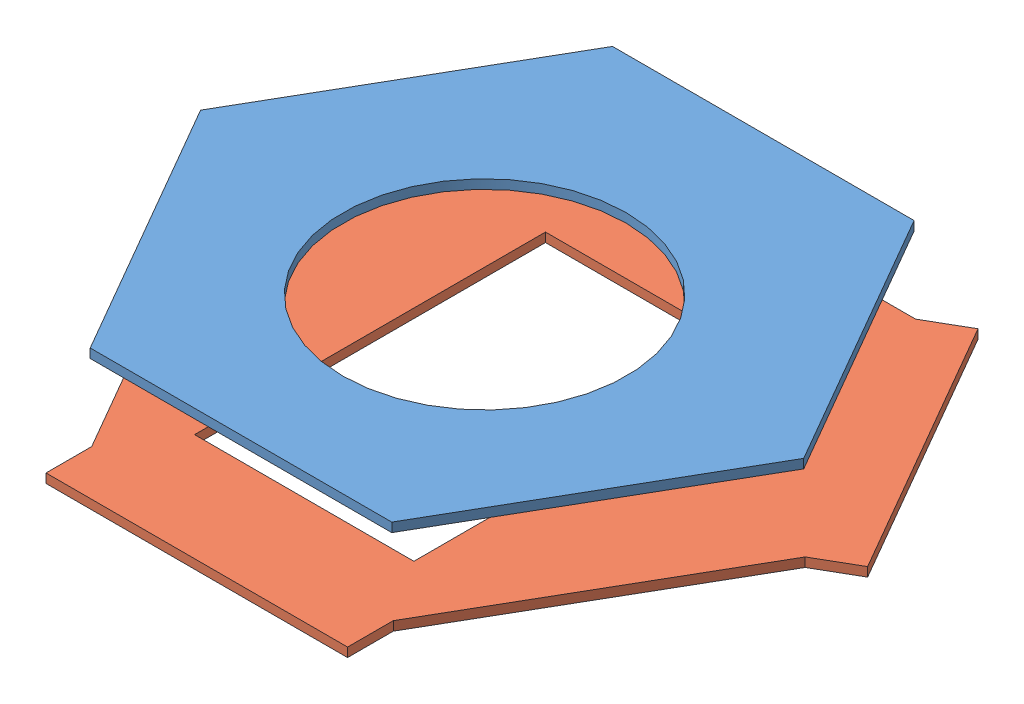
SolidWorks assembly Assem3, configuration Default. Lengths in mm.
Overall size (376.65 51.34 325.22).
2 component instances, 2 part files, 1 mates.
Components (placement in the parent):
- Mechanism Aperture-1: Mechanism Aperture [Default] at origin size (330 5 285.79)
- Mechanism Lock&Lock-1: Mechanism Lock&Lock [Default] at (0.7741 -46.3427 -0.04) size (376.65 5 325.22)
Mates (geometry in assembly coordinates):
- Parallel1: parallel aligned: plane of Mechanism Aperture-1 through (0 5 0) normal (0 1 0); plane of Mechanism Lock&Lock-1 through (0.7741 -41.3427 -0.04) normal (0 1 0)
